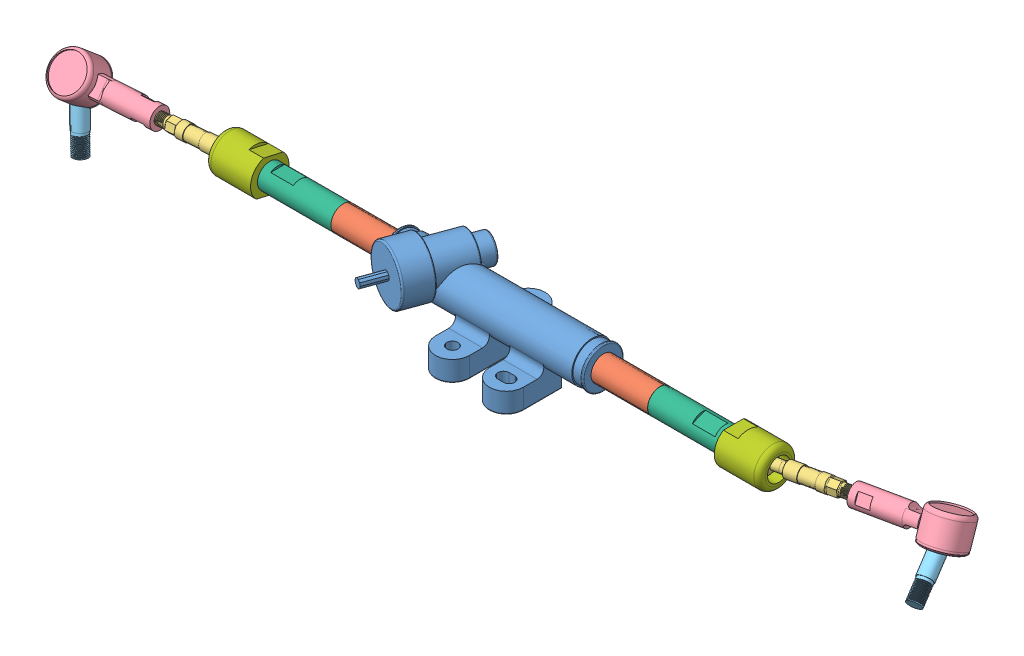
SolidWorks assembly steering assembly, configuration Default. Lengths in mm.
12 component instances, 7 part files, 21 mates.
Components (placement in the parent):
- prebuilt housing-1: prebuilt housing [Default] at (-22.0598 82.7728 134.0833) size (180 70.59 106.9)
- prebuilt rack-1: prebuilt rack [Default] at (207.9402 82.7728 134.0833) x (0 0.567124 0.823632) z (0 -0.823632 0.567124) size (22 312 22)
- prebuilt ball joint-1: prebuilt ball joint [Default] at (307.6464 83.1181 131.9326) x (0.071668 0.835779 0.544369) z (0.158838 -0.548371 0.821012) size (25 124 25)
- prebuilt ball joint-2: prebuilt ball joint [Default] at (-171.9431 82.2373 134.3416) x (-0.00868 -0.262981 -0.964762) z (0.046761 -0.963849 0.262312) size (25 124 25)
- prebuilt ball joint end-1: prebuilt ball joint end [Default] at (435.4862 98.9353 103.4029) x (-0.141765 -0.447158 -0.883149) z (-0.9847 -0.027626 0.172054) size (35 27 87.5)
- prebuilt ball joint end-2: prebuilt ball joint end [Default] at (-302.9701 85.2872 147.3534) x (0.046084 -0.764308 0.643203) z (0.998868 0.042837 -0.020664) size (35 27 87.5)
- ball end joint conection piece-1: ball end joint conection piece [Default] at (448.1924 91.453 109.9698) x (0.253129 -0.555984 0.791712) z (0.357201 -0.706825 -0.610578) size (65.5 25 25)
- ball end joint conection piece-2: ball end joint conection piece [Default] at (-290.9018 77.426 132.7227) x (0.166318 -0.973362 0.157812) z (-0.257576 -0.197369 -0.945886) size (65.5 25 25)
- extender-1: extender [Default] at (272.9402 82.7728 134.0833) x (0 0.924347 0.381554) z (0 -0.381554 0.924347) size (21.8 81.01 21.8)
- extender-2: extender [Default] at (-137.0598 82.7728 134.0833) x (0 -0.999985 -0.005515) z (0 -0.005515 0.999985) size (21.8 81.01 21.8)
- rackBallEnd-1: rackBallEnd [Default] at (-7.0598 82.7728 134.0833) x (0 -1 0) z (0 0 1) size (34 40.37 34)
- rackBallEnd-2: rackBallEnd [Default] at (142.9402 82.7728 134.0833) x (0 0.975815 -0.218598) z (0 0.218598 0.975815) size (34 40.37 34)
Mates (geometry in assembly coordinates):
- Concentric1: concentric anti-aligned: cylinder of prebuilt housing-1 through (157.9402 82.7728 134.0833) axis (-1 0 0) radius 11; cylinder of prebuilt rack-1 through (-72.0598 82.7728 134.0833) axis (1 0 0) radius 11
- Concentric4: concentric anti-aligned: cylinder of prebuilt ball joint-2 through (-213.8956 80.4382 135.2094) axis (-0.998868 -0.042837 0.020664) radius 6; circle of prebuilt ball joint end-2
- Concentric5: concentric anti-aligned: circle of prebuilt ball joint-1; circle of prebuilt ball joint end-1
- Concentric6: concentric: sphere of prebuilt ball joint end-1; sphere of ball end joint conection piece-1
- Concentric7: concentric: sphere of prebuilt ball joint end-2; sphere of ball end joint conection piece-2
- Parallel1: parallel anti-aligned: line of prebuilt ball joint end-2 through (-336.8968 81.5108 129.2357) axis (-0.023858 0.101359 -0.994564); line of ball end joint conection piece-2 through (-337.9976 86.1875 83.3467) axis (0.023858 -0.101359 0.994564)
- Concentric8: concentric anti-aligned: circle of prebuilt rack-1; circle of extender-2
- Coincident3: coincident anti-aligned: plane of prebuilt rack-1 through (-72.0598 95.1403 107.9625) normal (-1 0 0); plane of extender-2 through (-72.0598 82.7728 134.0833) normal (1 0 0)
- Concentric9: concentric anti-aligned: circle of prebuilt rack-1; circle of extender-1
- Coincident4: coincident anti-aligned: plane of prebuilt rack-1 through (207.9402 95.1403 107.9625) normal (1 0 0); plane of extender-1 through (207.9402 82.7728 134.0833) normal (-1 0 0)
- Concentric10: concentric anti-aligned: circle of extender-2; circle of rackBallEnd-2
- Coincident5: coincident anti-aligned: plane of extender-2 through (-137.0598 82.7728 134.0833) normal (-1 0 0); plane of rackBallEnd-2 through (-137.0598 82.7728 134.0833) normal (1 0 0)
- Concentric11: concentric anti-aligned: circle of extender-1; circle of rackBallEnd-1
- Coincident6: coincident anti-aligned: plane of extender-1 through (272.9402 82.7728 134.0833) normal (1 0 0); plane of rackBallEnd-1 through (272.9402 82.7728 134.0833) normal (-1 0 0)
- Concentric12: concentric: sphere of prebuilt ball joint-1; sphere of rackBallEnd-1
- Concentric13: concentric: sphere of prebuilt ball joint-2; sphere of rackBallEnd-2
- Coincident7: coincident: point of prebuilt housing-1; point of prebuilt rack-1
- Parallel2: parallel anti-aligned: plane of prebuilt ball joint-2 through (-222.8854 80.0526 135.3954) normal (-0.998868 -0.042837 0.020664); plane of prebuilt ball joint end-2 through (-232.889 79.5114 135.469) normal (0.998868 0.042837 -0.020664)
- Parallel3: parallel anti-aligned: plane of prebuilt ball joint-1 through (357.8661 84.527 123.1579) normal (0.9847 0.027626 -0.172054); plane of prebuilt ball joint end-1 through (367.9391 84.8096 121.3978) normal (-0.9847 -0.027626 0.172054)
- Lock1: lock: unknown of prebuilt ball joint-1; unknown of prebuilt ball joint end-1
- Lock2: lock: unknown of prebuilt ball joint-2; unknown of prebuilt ball joint end-2
